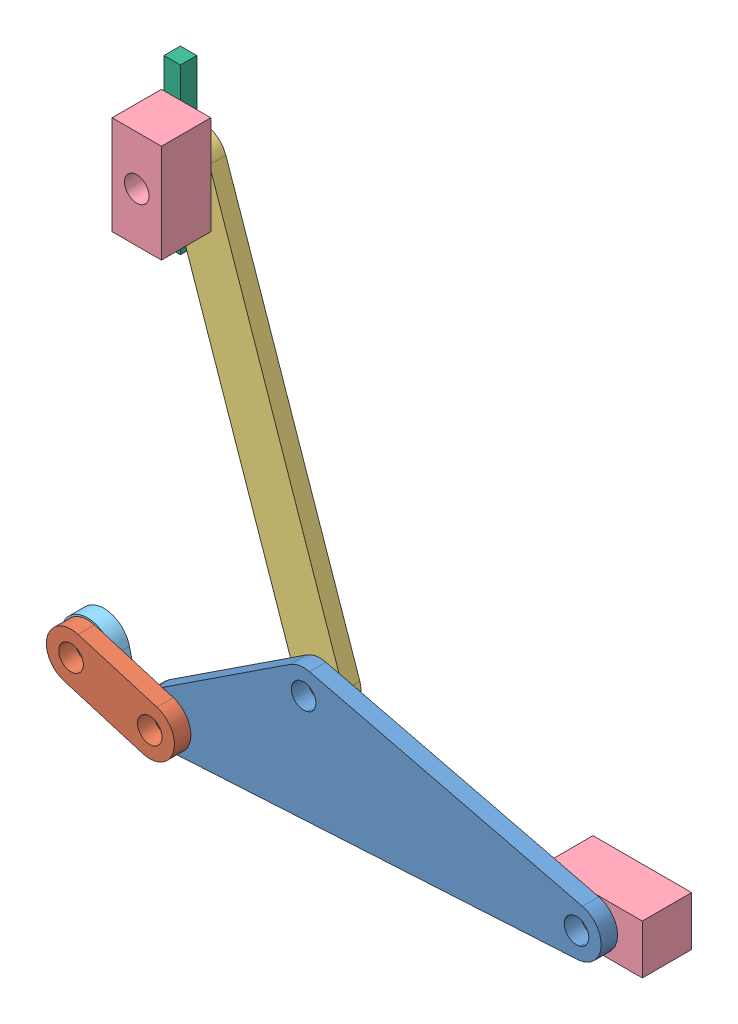
SolidWorks assembly Assem1, configuration Default. Lengths in mm.
Overall size (347.5 343.94 60).
7 component instances, 6 part files, 15 mates.
Components (placement in the parent):
- Link3-1: Link3 [Default] at (-152.6442 194.8339 565.713) x (0.998953 0.045752 0) z (0 0 1) size (279.98 81 10)
- Link2-1: Link2 [Default] at (-286.1746 199.7867 575.713) x (-0.003809 0.999993 0) z (0 0 1) size (44.5 77.85 10)
- Link5-1: Link5 [Default] at (-202.5778 254.6645 555.713) x (0.849606 0.527418 0) z (0 0 1) size (85.41 273.78 10)
- Slider-1: Slider [Default] at (-36.585 214.1047 535.713) size (60 30 30)
- Slider-2: Slider [Default] at (-284.0807 491.006 565.713) x (0 1 0) z (0 0 1) size (60 30 30)
- Rev ground-1: Rev ground [Default] at (-334.0807 199.1047 565.713) size (40 31 10)
- Ground-1: Ground [Default] at (-304.0807 478.0563 544.1901) size (10 100 10)
Mates (geometry in assembly coordinates):
- Concentric1: concentric aligned: cylinder of Link2-1 through (-334.0807 214.1047 585.713) axis (0 0 -1) radius 7.5; cylinder of Rev ground-1 through (-334.0807 214.1047 575.713) axis (0 0 -1) radius 7.5
- Coincident1: coincident anti-aligned: plane of Link2-1 through (-286.1746 199.7867 575.713) normal (0 0 -1); plane of Rev ground-1 through (-334.0807 214.1047 575.713) normal (0 0 1)
- Concentric6: concentric aligned: cylinder of Link3-1 through (-286.1746 199.7867 575.713) axis (0 0 -1) radius 7.5; cylinder of Link2-1 through (-286.1746 199.7867 585.713) axis (0 0 -1) radius 7.5
- Coincident2: coincident anti-aligned: plane of Link3-1 through (-152.6442 194.8339 575.713) normal (0 0 1); plane of Link2-1 through (-286.1746 199.7867 575.713) normal (0 0 -1)
- Concentric7: concentric aligned: cylinder of Link3-1 through (-36.585 214.1047 575.713) axis (0 0 -1) radius 7.5; cylinder of Slider-1 through (-36.585 214.1047 565.713) axis (0 0 -1) radius 7.5
- Coincident3: coincident anti-aligned: plane of Link3-1 through (-152.6442 194.8339 565.713) normal (0 0 -1); plane of Slider-1 through (-36.585 214.1047 565.713) normal (0 0 1)
- Distance2: distance = 0 mm aligned: plane of Slider-1 through (-66.585 199.1047 565.713) normal (0 -1 0); plane of Rev ground-1 through (-354.0807 199.1047 575.713) normal (0 -1 0)
- Concentric8: concentric aligned: cylinder of Link3-1 through (-202.5778 254.6645 575.713) axis (0 0 -1) radius 7.5; cylinder of Link5-1 through (-202.5778 254.6645 565.713) axis (0 0 -1) radius 7.5
- Coincident6: coincident anti-aligned: plane of Link3-1 through (-152.6442 194.8339 565.713) normal (0 0 -1); plane of Link5-1 through (-202.5778 254.6645 565.713) normal (0 0 1)
- Concentric9: concentric aligned: cylinder of Link5-1 through (-284.0807 491.006 565.713) axis (0 0 -1) radius 7.5; cylinder of Slider-2 through (-284.0807 491.006 595.713) axis (0 0 -1) radius 7.5
- Parallel5: parallel anti-aligned: plane of Slider-1 through (-6.585 199.1047 565.713) normal (1 0 0); plane of Slider-2 through (-299.0807 461.006 595.713) normal (-1 0 0)
- Coincident8: coincident anti-aligned: plane of Link5-1 through (-202.5778 254.6645 565.713) normal (0 0 1); plane of Slider-2 through (-284.0807 491.006 565.713) normal (0 0 -1)
- Perpendicular2: perpendicular: line of Rev ground-1 through (-354.0807 199.1047 565.713) axis (1 0 0); plane of Ground-1 through (-309.0807 428.0563 554.1901) normal (-1 0 0)
- Distance8: distance = 5 mm: line of Rev ground-1 through (-314.0807 199.1047 575.713) axis (0 0 -1); plane of Ground-1 through (-309.0807 428.0563 554.1901) normal (-1 0 0)
- Coincident14: coincident anti-aligned: plane of Slider-2 through (-299.0807 461.006 595.713) normal (-1 0 0); plane of Ground-1 through (-299.0807 428.0563 554.1901) normal (1 0 0)
